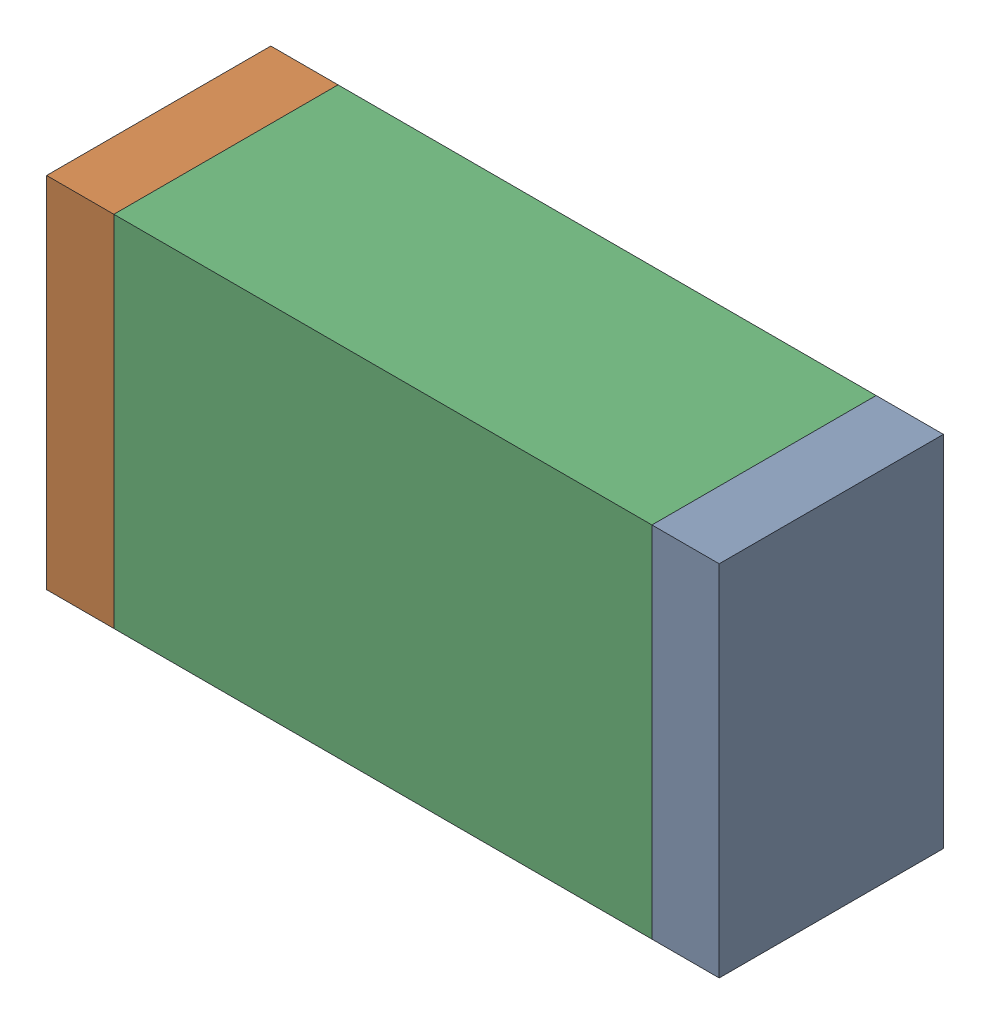
SolidWorks assembly R32, configuration Default. Lengths in mm.
Overall size (1.5 0.8 0.5).
6 component instances, 2 part files, 0 mates.
Components (placement in the parent):
- 836752496-1: 836752496 [Default] at (124.575 48.95 0) size (0.15 0.8 0.5)
  - Extruded_2-1: Extruded_2 [Default] at origin size (0.15 0.8 0.5)
- 836752496-2: 836752496 [Default] at (123.225 48.95 0) size (0.15 0.8 0.5)
  - Extruded_2-1: Extruded_2 [Default] at origin size (0.15 0.8 0.5)
- 836752368-1: 836752368 [Default] at (123.9 48.95 0) size (1.2 0.8 0.5)
  - Extruded-1: Extruded [Default] at origin size (1.2 0.8 0.5)
